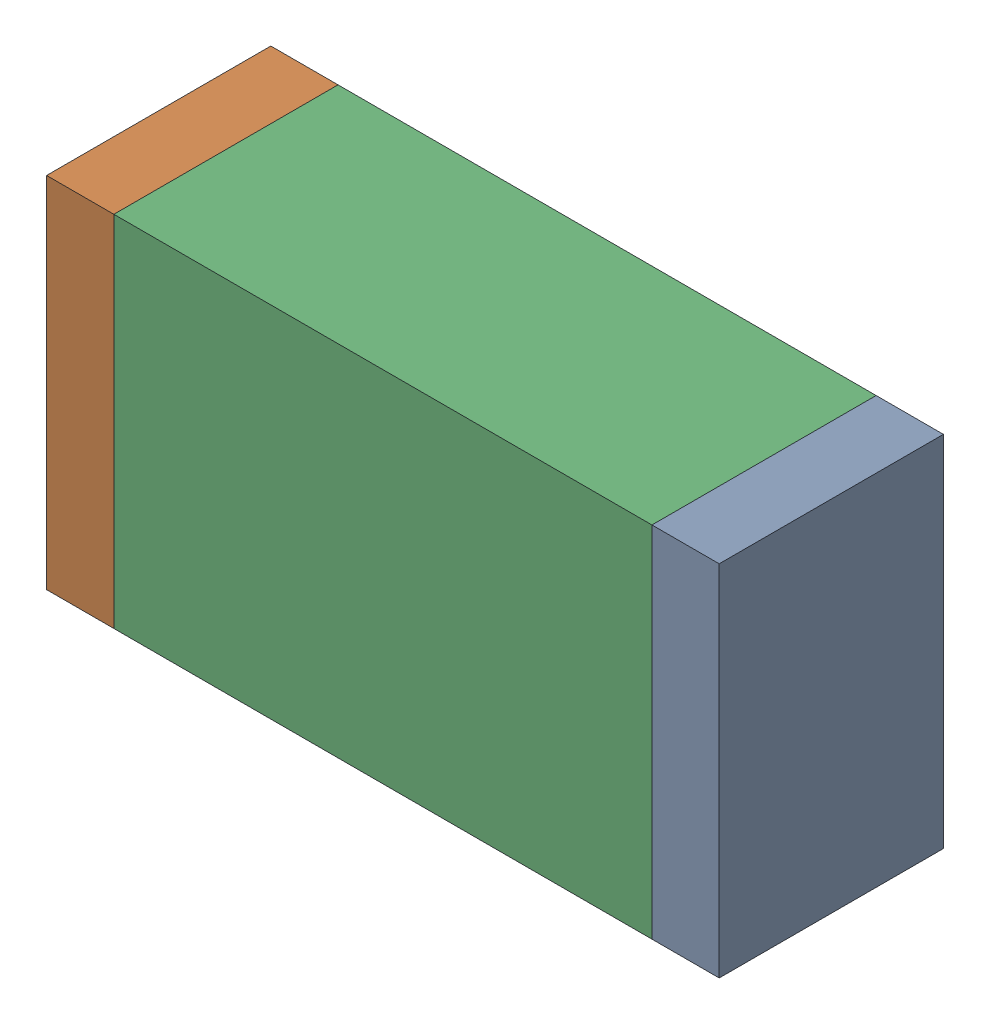
SolidWorks assembly R24, configuration Default. Lengths in mm.
Overall size (1.5 0.8 0.5).
6 component instances, 2 part files, 0 mates.
Components (placement in the parent):
- 836752496-1: 836752496 [Default] at (130.575 44.55 0) size (0.15 0.8 0.5)
  - Extruded_2-1: Extruded_2 [Default] at origin size (0.15 0.8 0.5)
- 836752496-2: 836752496 [Default] at (129.225 44.55 0) size (0.15 0.8 0.5)
  - Extruded_2-1: Extruded_2 [Default] at origin size (0.15 0.8 0.5)
- 836752368-1: 836752368 [Default] at (129.9 44.55 0) size (1.2 0.8 0.5)
  - Extruded-1: Extruded [Default] at origin size (1.2 0.8 0.5)
